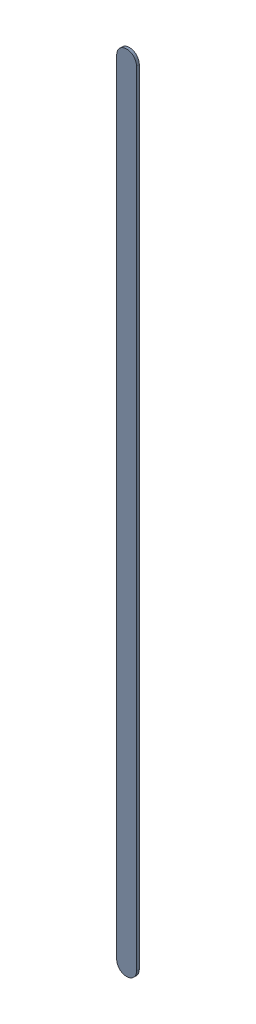
SolidWorks assembly Track (31.05mm,41.5mm)(31.05mm,51.55mm) on Top Layer, configuration Predeterminado. Lengths in mm.
Overall size (0.25 10.3 0.04).
2 component instances, 1 part files, 0 mates.
Components (placement in the parent):
- Track (31.05mm,41.5mm)(31.05mm,51.55mm) on Top Layer-1-1: Track (31.05mm,41.5mm)(31.05mm,51.55mm) on Top Layer-1 [Predeterminado] at (-68.317 -44.187 -0.0457) size (0.25 10.3 0.04)
  - Track (31.05mm,41.5mm)(31.05mm,51.55mm) on Top Layer-Part-1-1: Track (31.05mm,41.5mm)(31.05mm,51.55mm) on Top Layer-Part-1 [Predeterminado] at origin size (0.25 10.3 0.04)
